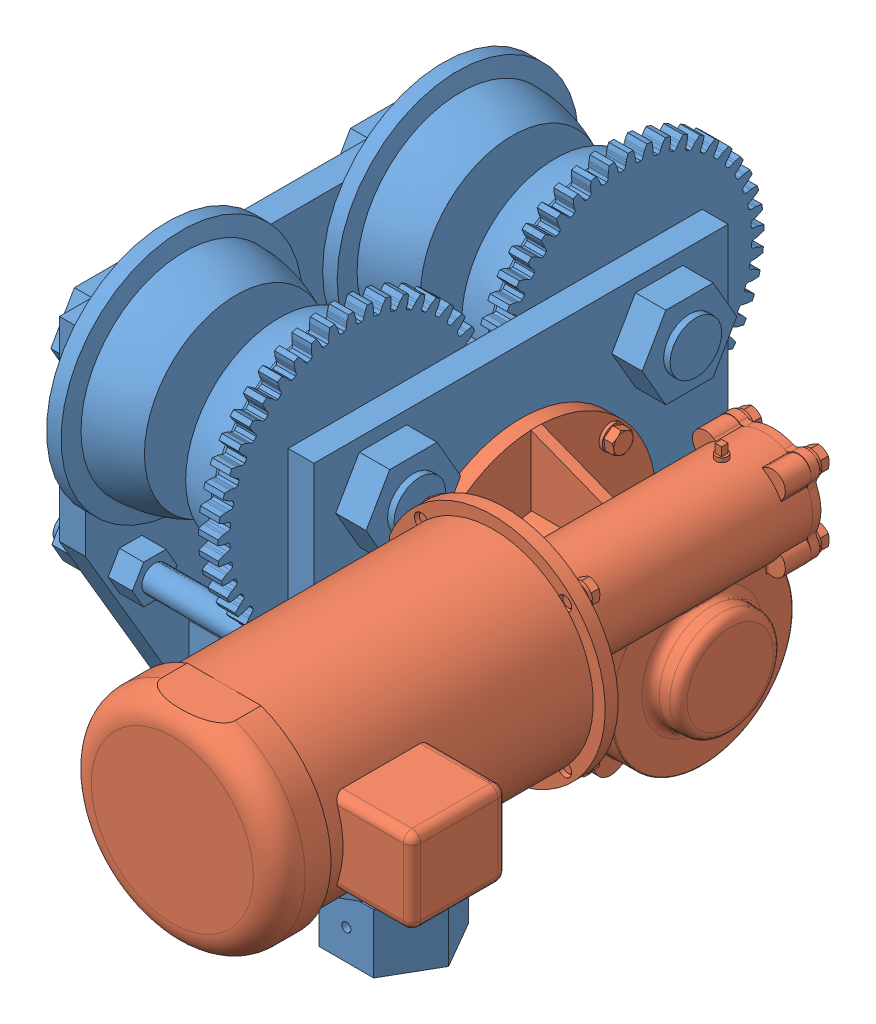
SolidWorks assembly M2630B-LH, configuration Default. Lengths in mm.
Overall size (453.1 492.84 570.37).
2 component instances, 2 part files, 3 mates.
Components (placement in the parent):
- Copy of M2630B-TROLLEY-SECTION^M2630B-LH-1: Copy of M2630B-TROLLEY-SECTION^M2630B-LH [S8x18.4#] at origin size (244.5 492.84 402.11) (virtual)
- Copy of SDT GEAR REDUCER LH M2630 TEMPLATE^M2630B-LH-1: Copy of SDT GEAR REDUCER LH M2630 TEMPLATE^M2630B-LH [Default] at (-22.2123 137.4775 0) x (-1 0 0) z (0 0 -1) size (238.76 237.33 457.42) (virtual)
Mates (geometry in assembly coordinates):
- Coincident1: coincident aligned: plane of Copy of M2630B-TROLLEY-SECTION^M2630B-LH-1 through (0 137.4775 0) normal (0 1 0); plane of Copy of SDT GEAR REDUCER LH M2630 TEMPLATE^M2630B-LH-1
- Coincident2: coincident anti-aligned: plane of Copy of M2630B-TROLLEY-SECTION^M2630B-LH-1 through (0 0 0) normal (0 0 1); plane of Copy of SDT GEAR REDUCER LH M2630 TEMPLATE^M2630B-LH-1
- Distance2: distance = 17.4625 mm aligned: plane of Copy of SDT GEAR REDUCER LH M2630 TEMPLATE^M2630B-LH-1 through (92.0877 137.4775 0) normal (-1 0 0); plane of Copy of M2630B-TROLLEY-SECTION^M2630B-LH-1 through (74.6252 0 -152.4) normal (-1 0 0)
